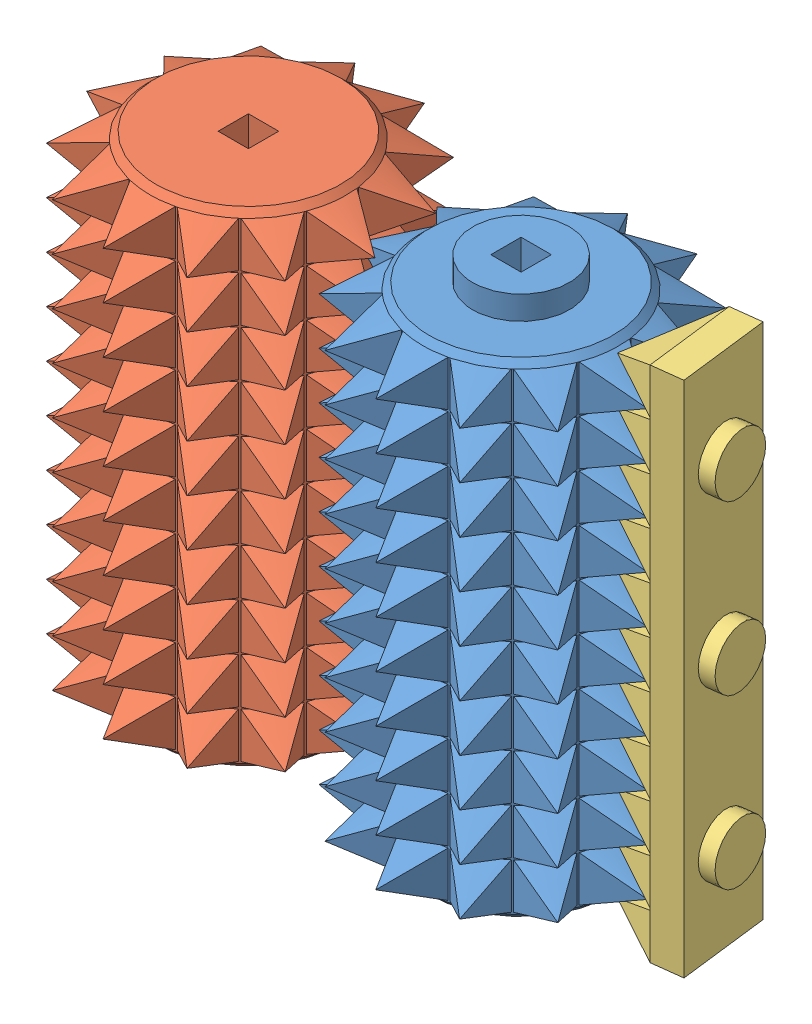
SolidWorks assembly Primary Grinder Cylinder Assembly, configuration Default. Lengths in mm.
Overall size (246.13 219.71 132.5).
3 component instances, 3 part files, 6 mates.
Components (placement in the parent):
- Primary grinder cylinder #1-1: Primary grinder cylinder #1 [Default] at (-40.249 -100.3023 16.1158) size (121.02 213.11 120.16)
- Primary grinder cylinder #2-2: Primary grinder cylinder #2 [Default] at (-142.2993 -90.3963 28.4563) size (121.02 213.11 120.16)
- Primary Grinder Wall Spikes #1-1: Primary Grinder Wall Spikes #1 [Default] at (27.1597 -106.9063 -2.5505) x (0 1 0) z (0.121465 0 0.992596) size (217.17 38.85 38.1)
Mates (geometry in assembly coordinates):
- Coincident3: coincident aligned: plane of Primary grinder cylinder #1-1 through (-40.249 112.8037 16.1158) normal (0 1 0); plane of Primary grinder cylinder #2-2 through (-142.2993 112.8037 28.4563) normal (0 1 0)
- Parallel1: parallel anti-aligned: line of Primary grinder cylinder #1-1 through (-46.599 112.8037 9.7658) axis (0 0 1); line of Primary grinder cylinder #2-2 through (-135.9493 112.8037 34.8063) axis (0 0 -1)
- Distance1: distance = 20.32 mm: point of Primary grinder cylinder #2-2; point of Primary grinder cylinder #1-1
- Perpendicular2: perpendicular: line of Primary Grinder Wall Spikes #1-1 through (32.3814 110.2637 -12.7855) axis (0.121465 0 0.992596); line of assembly
- Distance4: distance = 2.54 mm aligned: plane of Primary grinder cylinder #1-1 through (-40.249 112.8037 16.1158) normal (0 1 0); plane of Primary Grinder Wall Spikes #1-1 through (19.6998 110.2637 -11.2337) normal (0 1 0)
- Distance6: distance = 34.3662 mm aligned: plane of Primary Grinder Wall Spikes #1-1 through (33.5384 -106.9063 -3.331) normal (0.992596 0 -0.121465); cylinder of Primary grinder cylinder #1-1 through (-40.249 102.8977 16.1158) axis (0 -1 0) radius 41.2369
